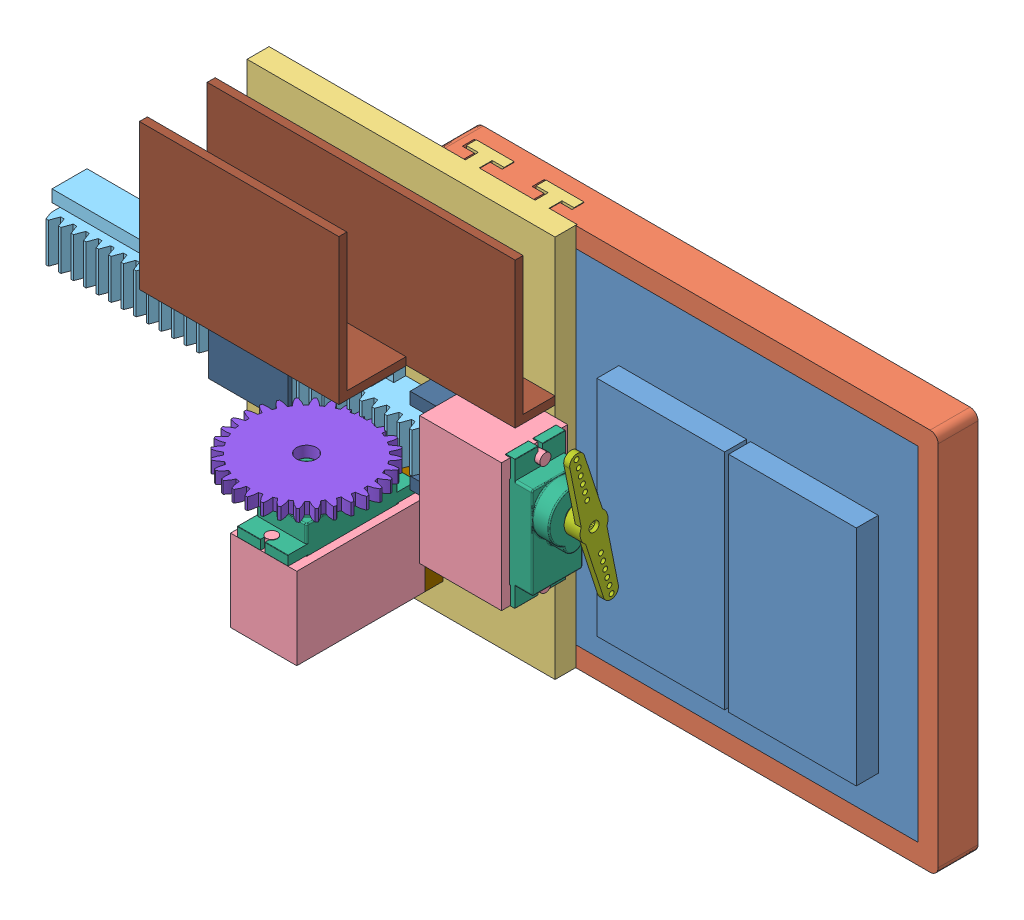
SolidWorks assembly 总装配体v3, configuration 默认. Lengths in mm.
Overall size (208.08 96.14 64.96).
13 component instances, 11 part files, 35 mates.
Components (placement in the parent):
- 开关建模-1: 开关建模 [默认] at origin size (86 86 15.5)
- 底座框架-1: 底座框架 [默认] at origin size (126 96 10)
- 活动底板-2: 活动底板 [默认] at (-39.7003 6.3474 -133.25) size (77.19 96.05 11.25)
- 舵机外壳v2-2: 舵机外壳v2 [默认] at (-56.5768 -7.0177 7.25) x (0 -1 0) z (0 0 1) size (32.1 23 16.6)
- 带槽齿条-1: 带槽齿条 [默认] at (-80.3748 8.9243 -166.694) size (100 15 11)
- SG90_Model_B.step-1: SG90_Model_B.step [默认] at (-56.5768 -6.9177 13.35) x (0 0 1) z (-1 0 0) size (12.61 32.4 29.2)
- SG90_Arm_04_Custom.step-1: SG90_Arm_04_Custom.step [默认] at (-24.8768 -1.7177 13.35) x (0 -0.253839 0.967246) z (-1 0 0) size (7 37 4)
- spur gear_gb-1: spur gear_gb [GB - Spur gear 1M 32T 20PA 3FW ---S32A75H50L5.0N] at (-79.2886 -4.1779 31) x (0 -1 0) z (-0.702378 0 0.711805) size (3 33.89 33.89)
- SG90_Model_B.step-2: SG90_Model_B.step [默认] at (-79.2886 -35.8779 25.8) x (1 0 0) z (0 -1 0) size (12.61 32.4 29.2)
- 舵机外壳v2-3: 舵机外壳v2 [默认] at (-85.3886 -37.0779 25.9) x (0 0 -1) z (1 0 0) size (32.1 23 16.6)
- 零件3^总装配体v3-1: 零件3^总装配体v3 [默认] at (-39.7003 6.3474 5.25) size (16.6 20.5 4.6) (virtual)
- 零件4^总装配体v3-1: 零件4^总装配体v3 [默认] at (-39.7003 6.3474 5.25) size (56.47 21.4 13.1) (virtual)
- 零件5^总装配体v3-1: 零件5^总装配体v3 [默认] at (-39.7003 6.3474 5.25) size (77.19 36.47 27) (virtual)
Mates (geometry in assembly coordinates):
- 重合1: coincident anti-aligned: plane of 开关建模-1 through (-43 43 -131.6224) normal (-1 0 0); plane of 底座框架-1 through (-43 43 -10) normal (1 0 0)
- 重合2: coincident anti-aligned: plane of 开关建模-1 through (-43 -43 -131.6224) normal (0 -1 0); plane of 底座框架-1 through (-43 -43 -10) normal (0 1 0)
- 重合3: coincident anti-aligned: plane of 底座框架-1 through (-74.2475 -54.6576 -6) normal (0 0 1); plane of 活动底板-2 through (-64.2525 -53.9563 -6) normal (0 0 -1)
- 重合4: coincident anti-aligned: plane of 底座框架-1 through (-46.7525 -54.6576 -3) normal (-1 0 0); plane of 活动底板-2 through (-46.7525 -53.9563 -3.5) normal (1 0 0)
- 重合6: coincident aligned: plane of 开关建模-1 through (0 0 0) normal (0 0 1); plane of 底座框架-1 through (0 0 0) normal (0 0 1)
- 重合7: coincident anti-aligned: plane of 舵机外壳v2-2 through (-60.0768 21.2732 19.45) normal (-1 0 0); plane of 带槽齿条-1 through (-60.0768 -10.6779 5.25) normal (1 0 0)
- 重合8: coincident anti-aligned: plane of 活动底板-2 through (0.25 0.144 5.25) normal (0 0 1); plane of 舵机外壳v2-2 through (-56.5768 -7.0177 5.25) normal (0 0 -1)
- 重合10: coincident anti-aligned: plane of 舵机外壳v2-2 through (-56.5768 4.5323 19.45) normal (1 0 0); plane of SG90_Model_B.step-1 through (-56.5768 -6.9177 13.35) normal (-1 0 0)
- 平行1: parallel anti-aligned: plane of 舵机外壳v2-2 through (-56.5768 -18.5677 19.45) normal (0 1 0); plane of SG90_Model_B.step-1 through (-56.5768 -18.4177 19.65) normal (0 -1 0)
- 距离1: distance = 1 mm anti-aligned: plane of SG90_Arm_04_Custom.step-1 through (-28.8768 -1.7177 13.35) normal (-1 0 0); plane of SG90_Model_B.step-1 through (-29.8768 -2.6677 13.35) normal (1 0 0)
- 同心8: concentric aligned: circle of SG90_Model_B.step-1; circle of SG90_Arm_04_Custom.step-1
- 同心12: concentric anti-aligned: circle of 舵机外壳v2-2; circle of SG90_Model_B.step-1
- 距离2: distance = 2.2102 mm aligned: plane of 带槽齿条-1 through (-60.0768 -0.6779 16.25) normal (0 1 0); plane of 舵机外壳v2-2 through (-39.5768 1.5323 15.75) normal (0 1 0)
- 宽度2: width anti-aligned: plane of GB - Spur gear 1M 32T 20PA 3FW ---S32A75H50L5.0N-1 through (-79.2886 -7.1779 31) normal (0 -1 0); plane of GB - Spur gear 1M 32T 20PA 3FW ---S32A75H50L5.0N-1 through (-79.2886 -4.1779 31) normal (0 1 0); plane of 带槽齿条-1 through (-60.0768 -0.6779 16.25) normal (0 1 0); plane of 带槽齿条-1 through (-60.0768 -10.6779 16.25) normal (0 -1 0)
- 相切1: tangent anti-aligned: plane of 带槽齿条-1 through (-79.3708 -10.6779 14) normal (0 0 1); cylinder of GB - Spur gear 1M 32T 20PA 3FW ---S32A75H50L5.0N-1 through (-79.2886 5.8221 31) axis (0 1 0) radius 17
- 重合19: coincident aligned: line of 舵机外壳v2-2 through (-60.0768 -23.0677 5.25) axis (0 1 0); line of 带槽齿条-1 through (-60.0768 -10.6779 5.25) axis (0 1 0)
- 同心13: concentric anti-aligned: circle of GB - Spur gear 1M 32T 20PA 3FW ---S32A75H50L5.0N-1; circle of SG90_Model_B.step-2
- 距离3: distance = 2 mm anti-aligned: plane of SG90_Model_B.step-2 through (-79.2886 -9.1779 30.05) normal (0 1 0); plane of spur gear_gb-1 through (-79.2886 -7.1779 31) normal (0 -1 0)
- 同心14: concentric anti-aligned: circle of SG90_Model_B.step-2; circle of 舵机外壳v2-3
- 平行4: parallel anti-aligned: plane of SG90_Model_B.step-2 through (-72.9886 -35.8779 37.3) normal (1 0 0); plane of 舵机外壳v2-3 through (-72.7886 -37.0779 25.9) normal (-1 0 0)
- 重合21: coincident anti-aligned: plane of SG90_Model_B.step-2 through (-79.2886 -20.0779 39.65) normal (0 -1 0); plane of 舵机外壳v2-3 through (-73.1886 -20.0779 37.45) normal (0 1 0)
- 平行5: parallel anti-aligned: plane of 活动底板-2 through (0.25 0.144 5.25) normal (0 0 1); plane of 舵机外壳v2-3 through (-73.1886 -41.5779 9.85) normal (0 0 -1)
- 在位1: in place: plane of 活动底板-2 through (0.25 0.144 5.25) normal (0 0 1); plane of ? through (0 0 5.25) normal (0 0 1); moOrthogonalPlaneRef_w of 活动底板-2 through (0.25 0.144 5.25) normal (0 0 1); plane of ? through (0 0 5.25) normal (0 1 0); plane of 活动底板-2 through (0.25 0.144 5.25) normal (0 0 1); plane of ? through (0 0 5.25) normal (1 0 0); plane of 活动底板-2 through (0.25 0.144 5.25) normal (0 0 1); unknown of ?
- 重合22: coincident aligned: plane of ?; plane of ?
- 重合23: coincident aligned: moOrthogonalPlaneRef_w of 活动底板-2 through (-39.7003 6.3474 5.25) normal (0 1 0); plane of 零件3^总装配体v2-1 through (-39.7003 6.3474 5.25) normal (0 1 0)
- 重合24: coincident anti-aligned: moOrthogonalPlaneRef_w of 活动底板-2 through (-39.7003 6.3474 5.25) normal (-1 0 0); plane of 零件3^总装配体v2-1 through (-39.7003 6.3474 5.25) normal (1 0 0)
- 在位2: in place: plane of 活动底板-2 through (0.25 0.144 5.25) normal (0 0 1); plane of ? through (0 0 5.25) normal (0 0 1); plane of 活动底板-2 through (0.25 0.144 5.25) normal (0 0 1); plane of ? through (0 0 5.25) normal (0 1 0); plane of 活动底板-2 through (0.25 0.144 5.25) normal (0 0 1); plane of ? through (0 0 5.25) normal (1 0 0); plane of 活动底板-2 through (0.25 0.144 5.25) normal (0 0 1); unknown of ?
- 重合25: coincident aligned: plane of ?; plane of ?
- 重合26: coincident aligned: moOrthogonalPlaneRef_w of 活动底板-2 through (-39.7003 6.3474 5.25) normal (0 1 0); plane of 零件4^总装配体v2-1 through (-39.7003 6.3474 5.25) normal (0 1 0)
- 重合27: coincident anti-aligned: moOrthogonalPlaneRef_w of 活动底板-2 through (-39.7003 6.3474 5.25) normal (-1 0 0); plane of 零件4^总装配体v2-1 through (-39.7003 6.3474 5.25) normal (1 0 0)
- 在位3: in place: plane of 活动底板-2 through (0.25 0.144 5.25) normal (0 0 1); plane of ? through (0 0 5.25) normal (0 0 1); plane of 活动底板-2 through (0.25 0.144 5.25) normal (0 0 1); plane of ? through (0 0 5.25) normal (0 1 0); plane of 活动底板-2 through (0.25 0.144 5.25) normal (0 0 1); plane of ? through (0 0 5.25) normal (1 0 0); plane of 活动底板-2 through (0.25 0.144 5.25) normal (0 0 1); unknown of ?
- 重合22: coincident aligned: plane of ?; plane of ?
- 重合23: coincident aligned: moOrthogonalPlaneRef_w of 活动底板-2 through (-39.7003 6.3474 5.25) normal (0 1 0); plane of 零件5^总装配体v2-1 through (-39.7003 6.3474 5.25) normal (0 1 0)
- 重合24: coincident anti-aligned: moOrthogonalPlaneRef_w of 活动底板-2 through (-39.7003 6.3474 5.25) normal (-1 0 0); plane of 零件5^总装配体v2-1 through (-39.7003 6.3474 5.25) normal (1 0 0)
- 宽度3: width anti-aligned: plane of 带槽齿条-1 through (-49.9989 4.3221 14) normal (0 1 0); plane of 零件4^总装配体v3-1 through (-60.0768 -10.6779 16.25) normal (0 -1 0); plane of 带槽齿条-1 through (-96.5457 4.5221 36.4498) normal (0 -1 0); plane of 零件4^总装配体v3-1 through (-96.5457 -10.8779 36.4498) normal (0 1 0)
